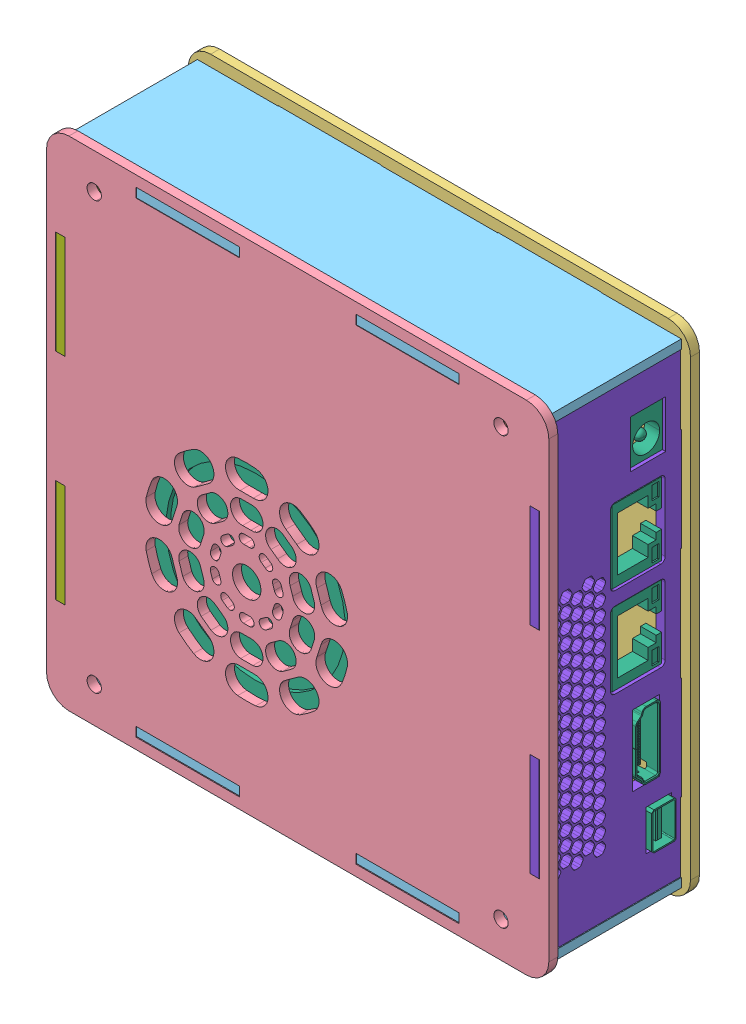
SolidWorks assembly NUC, configuration 默认. Lengths in mm.
Overall size (112 111 35).
9 component instances, 8 part files, 22 mates.
Components (placement in the parent):
- M3×10铜柱-1: M3×10铜柱 [默认] at (-17.5613 40.9614 -17.2159) x (0.981586 0.191019 0) z (0.191019 -0.981586 0) size (5.31 11 4.71)
- M3×16铜柱-1: M3×16铜柱 [默认] at (-17.5613 40.9614 -4.6159) x (-0.007545 0.999972 0) z (0.999972 0.007545 0) size (5.31 17 4.71)
- 上板-1: 上板 [默认] at (-62.9113 -6.5886 -19.2159) size (112 111 2)
- 下板-1: 下板 [默认] at (-62.9113 -6.5886 12.3841) size (112 111 2)
- 侧板-1: 侧板 [默认] at (-62.9113 -59.5886 -2.4659) size (107.9 2 33.5)
- 侧板-2: 侧板 [默认] at (-62.9113 44.4114 -2.4659) size (107.9 2 33.5)
- 主板_官方-3: 主板_官方 [默认] at (-61.6123 -6.6515 -6.2159) x (0 -1 0) z (0 0 -1) size (102.9 109.8 33)
- 非通风板-1: 非通风板 [默认] at (-114.7613 -6.5886 -2.3659) x (0 1 0) z (0 0 1) size (101.8 2 33.5)
- 通风板-1: 通风板 [默认] at (-11.0613 -6.5886 -2.3659) x (0 -1 0) z (0 0 1) size (101.8 2 33.5)
Mates (geometry in assembly coordinates):
- 重合6: coincident anti-aligned: plane of 上板-1 through (-26.9113 -57.5886 -17.2159) normal (0 -1 0); plane of 侧板-1 through (-62.9113 -57.5886 -2.4659) normal (0 1 0)
- 重合7: coincident aligned: plane of 上板-1 through (-62.9113 -6.5886 -19.2159) normal (0 0 -1); plane of 侧板-1 through (-49.9113 -59.5886 -19.2159) normal (0 0 -1)
- 重合8: coincident anti-aligned: plane of 上板-1 through (-26.9113 -57.5886 -17.2159) normal (-1 0 0); plane of 侧板-1 through (-26.9113 -59.5886 -17.2159) normal (1 0 0)
- 重合9: coincident anti-aligned: plane of 上板-1 through (-75.9113 44.4114 -17.2159) normal (0 1 0); plane of 侧板-2 through (-62.9113 44.4114 -2.4659) normal (0 -1 0)
- 重合10: coincident aligned: plane of 上板-1 through (-62.9113 -6.5886 -19.2159) normal (0 0 -1); plane of 侧板-2 through (-98.9113 44.4114 -19.2159) normal (0 0 -1)
- 重合11: coincident anti-aligned: plane of 上板-1 through (-98.9113 44.4114 -17.2159) normal (1 0 0); plane of 侧板-2 through (-98.9113 44.4114 -17.2159) normal (-1 0 0)
- 同心1: concentric anti-aligned: cylinder of M3×10铜柱-1 through (-17.5613 40.9614 -6.2159) axis (0 0 1) radius 1.25; cylinder of 主板_官方-3 through (-17.5613 40.9614 -6.2159) axis (0 0 -1) radius 1.75
- 重合12: coincident anti-aligned: plane of M3×10铜柱-1 through (-17.5613 40.9614 -6.2159) normal (0 0 1); plane of 主板_官方-3 through (-61.6123 -6.6515 -6.2159) normal (0 0 -1)
- 重合13: coincident anti-aligned: plane of M3×18铜柱-1 through (-17.5613 40.9614 -4.6159) normal (0 0 -1); plane of 主板_官方-3 through (-61.6123 -6.6515 -4.6159) normal (0 0 1)
- 同心2: concentric anti-aligned: cylinder of M3×18铜柱-1 through (-17.5613 40.9614 12.3841) axis (0 0 1) radius 1.25; cylinder of 主板_官方-3 through (-17.5613 40.9614 -6.2159) axis (0 0 -1) radius 1.75
- 同心3: concentric anti-aligned: cylinder of M3×10铜柱-1 through (-17.5613 40.9614 -6.2159) axis (0 0 1) radius 1.25; cylinder of 上板-1 through (-17.5613 40.9614 -17.2159) axis (0 0 -1) radius 1.6
- 重合14: coincident: plane of 上板-1 through (-62.9113 -6.5886 -17.2159) normal (0 0 1); line of M3×10铜柱-1 through (-20.187 40.5622 -17.2159) axis (0.624478 -0.781043 0)
- 重合15: coincident anti-aligned: plane of 上板-1 through (-62.9113 -6.5886 -17.2159) normal (0 0 1); plane of M3×10铜柱-1 through (-17.5613 40.9614 -17.2159) normal (0 0 -1)
- 重合16: coincident anti-aligned: plane of 下板-1 through (-62.9113 -6.5886 12.3841) normal (0 0 -1); plane of M3×18铜柱-1 through (-17.5613 40.9614 12.3841) normal (0 0 1)
- 同心4: concentric anti-aligned: cylinder of 下板-1 through (-17.5613 40.9614 14.3841) axis (0 0 -1) radius 1.6; cylinder of M3×18铜柱-1 through (-17.5613 40.9614 12.3841) axis (0 0 1) radius 1.25
- 重合17: coincident aligned: plane of 下板-1 through (-62.9113 -6.5886 14.3841) normal (0 0 1); plane of 非通风板-1 through (-114.7613 -42.0886 14.3841) normal (0 0 1)
- 重合18: coincident anti-aligned: plane of 上板-1 through (-114.7613 -19.0886 -17.2159) normal (-1 0 0); plane of 非通风板-1 through (-114.7613 -6.5886 -2.3659) normal (1 0 0)
- 重合19: coincident anti-aligned: plane of 上板-1 through (-116.8613 -19.0886 -17.2159) normal (0 -1 0); plane of 非通风板-1 through (-114.7613 -19.0886 -17.1159) normal (0 1 0)
- 同心5: concentric aligned: cylinder of 上板-1 through (-108.2613 40.9614 -17.2159) axis (0 0 -1) radius 1.6; cylinder of 主板_官方-3 through (-108.2622 40.9614 -6.2159) axis (0 0 -1) radius 1.75
- 重合20: coincident aligned: plane of 下板-1 through (-62.9113 -6.5886 14.3841) normal (0 0 1); plane of 通风板-1 through (-11.0613 -19.0886 14.3841) normal (0 0 1)
- 重合21: coincident anti-aligned: plane of 上板-1 through (-11.0613 28.9114 -17.2159) normal (1 0 0); plane of 通风板-1 through (-11.0613 -6.5886 -2.3659) normal (-1 0 0)
- 重合22: coincident anti-aligned: plane of 上板-1 through (-8.9613 28.9114 -17.2159) normal (0 -1 0); plane of 通风板-1 through (-11.0613 28.9114 -17.1159) normal (0 1 0)
